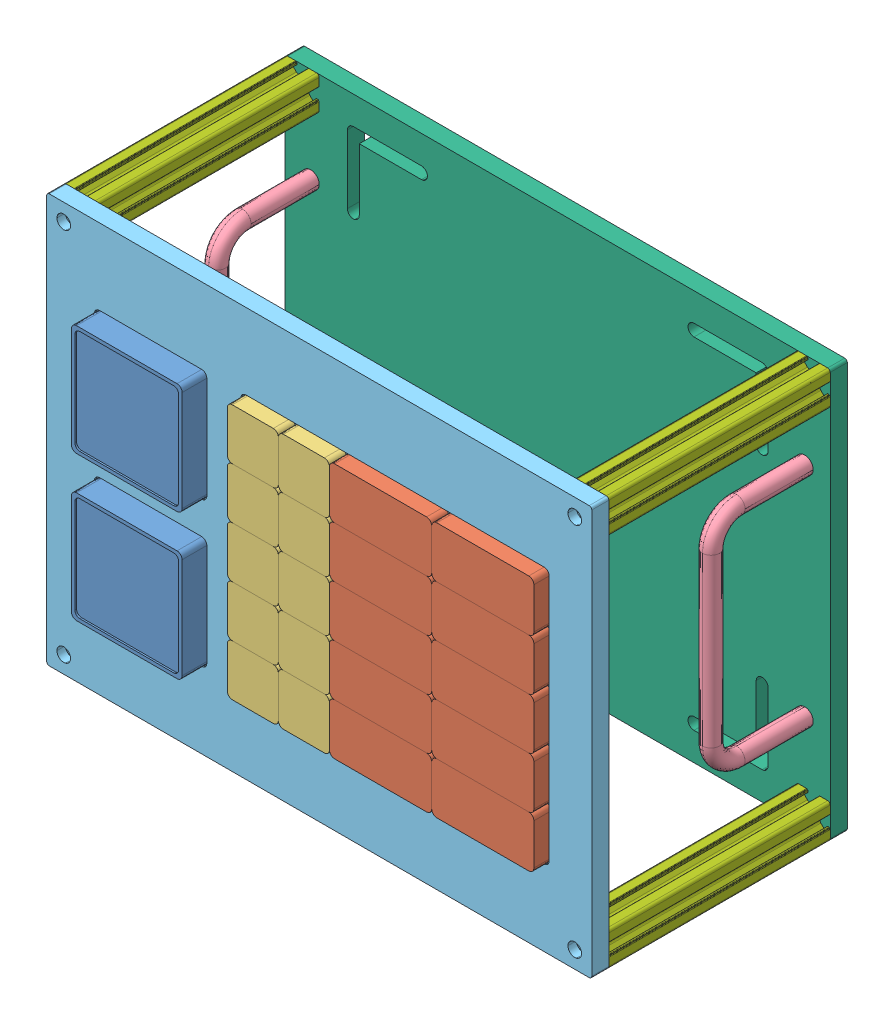
SolidWorks assembly 码垛, configuration 默认. Lengths in mm.
Overall size (320 240 164).
31 component instances, 7 part files, 0 mates.
Components (placement in the parent):
- 码垛.STEP-1: 码垛.STEP [默认] at origin size (320 240 164)
  - ________A.STEP-1: ________A.STEP [默认] at (3.7581 19.9838 24.0213) size (65 65 15)
  - ____22.STEP-1: ____22.STEP [默认] at (207.7581 37.9838 24.0213) size (60 30 10)
  - ____22.STEP-2: ____22.STEP [默认] at (147.7581 37.9838 24.0213) size (60 30 10)
  - ____22.STEP-3: ____22.STEP [默认] at (207.7581 7.9838 24.0213) size (60 30 10)
  - ____22.STEP-4: ____22.STEP [默认] at (147.7581 7.9838 24.0213) size (60 30 10)
  - ____22.STEP-5: ____22.STEP [默认] at (207.7581 -22.0162 24.0213) size (60 30 10)
  - ____22.STEP-6: ____22.STEP [默认] at (147.7581 -22.0162 24.0213) size (60 30 10)
  - ____22.STEP-7: ____22.STEP [默认] at (207.7581 -52.0162 24.0213) size (60 30 10)
  - ____22.STEP-8: ____22.STEP [默认] at (147.7581 -52.0162 24.0213) size (60 30 10)
  - ____11.STEP-1: ____11.STEP [默认] at (102.7581 37.9838 24.0213) size (30 30 10)
  - ____11.STEP-2: ____11.STEP [默认] at (72.7581 37.9838 24.0213) size (30 30 10)
  - ____11.STEP-3: ____11.STEP [默认] at (102.7581 7.9838 24.0213) size (30 30 10)
  - ____11.STEP-4: ____11.STEP [默认] at (72.7581 7.9838 24.0213) size (30 30 10)
  - ____11.STEP-5: ____11.STEP [默认] at (102.7581 -22.0162 24.0213) size (30 30 10)
  - ____11.STEP-6: ____11.STEP [默认] at (72.7581 -22.0162 24.0213) size (30 30 10)
  - ____11.STEP-7: ____11.STEP [默认] at (102.7581 -52.0162 24.0213) size (30 30 10)
  - ____11.STEP-8: ____11.STEP [默认] at (72.7581 -52.0162 24.0213) size (30 30 10)
  - ____11.STEP-9: ____11.STEP [默认] at (102.7581 -82.0162 24.0213) size (30 30 10)
  - ____11.STEP-10: ____11.STEP [默认] at (72.7581 -82.0162 24.0213) size (30 30 10)
  - ____22.STEP-9: ____22.STEP [默认] at (207.7581 -82.0162 24.0213) size (60 30 10)
  - ____22.STEP-10: ____22.STEP [默认] at (147.7581 -82.0162 24.0213) size (60 30 10)
  - ________A.STEP-2: ________A.STEP [默认] at (3.7581 -65.0162 24.0213) x (0 -1 0) z (0 0 1) size (65 65 15)
  - ____.STEP-1: ____.STEP [默认] at (-42.2419 -22.5162 -114.9787) x (0 -1 0) z (-1 0 0) size (138 60 10)
  - ____.STEP-2: ____.STEP [默认] at (247.7581 -22.5162 -114.9787) x (0 -1 0) z (-1 0 0) size (138 60 10)
  - ________B - 02.STEP-1: ________B - 02.STEP [默认] at (102.7581 -22.5162 15.0213) size (320 240 10)
  - ________C.STEP-1: ________C.STEP [默认] at (102.7581 -22.5162 -124.9787) size (320 240 10)
  - BET-6-2020--150-______.STEP-1: BET-6-2020--150-______.STEP [默认] at (-1276.8556 -688.0169 -114.9787) size (20 20 130)
  - BET-6-2020--150-______.STEP-2: BET-6-2020--150-______.STEP [默认] at (-1276.8556 -468.0169 -114.9787) size (20 20 130)
  - BET-6-2020--150-______.STEP-3: BET-6-2020--150-______.STEP [默认] at (-976.8556 -688.0169 -114.9787) size (20 20 130)
  - BET-6-2020--150-______.STEP-4: BET-6-2020--150-______.STEP [默认] at (-976.8556 -468.0169 -114.9787) size (20 20 130)
